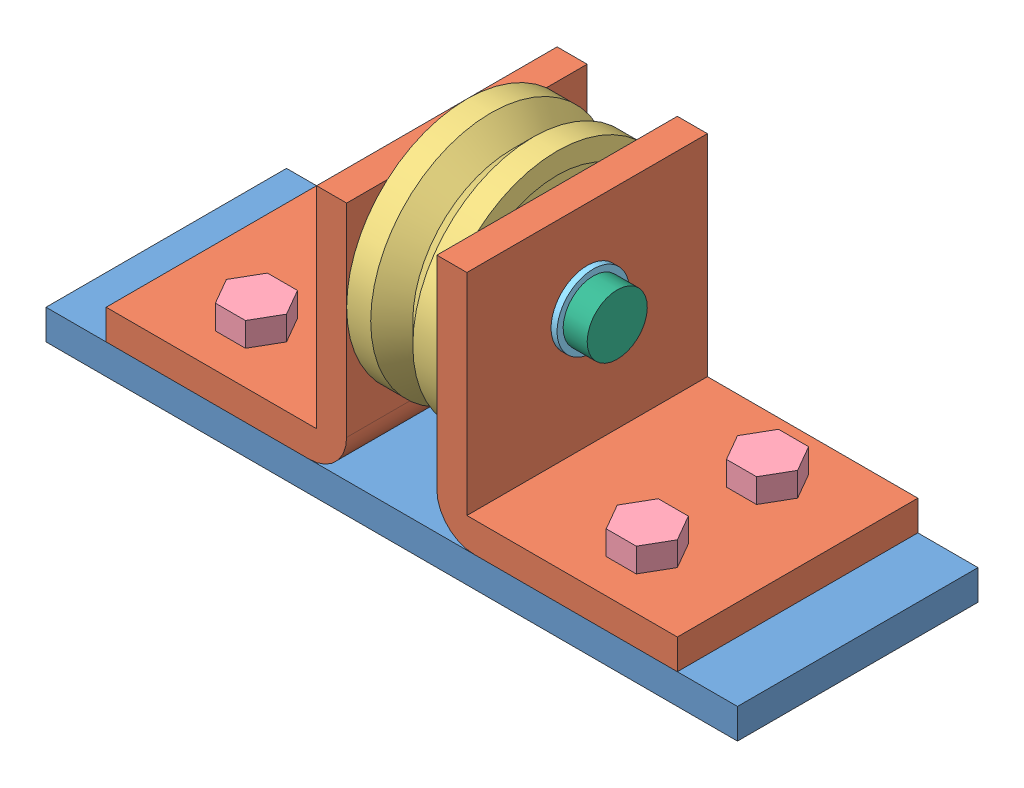
SolidWorks assembly Assem1, configuration Default. Lengths in mm.
Overall size (115 50 40).
13 component instances, 8 part files, 27 mates.
Components (placement in the parent):
- Part1-1: Part1 [Default] at origin size (115 5 40)
- Part2-1: Part2 [Default] at (12.5 7.5 0) size (40 40 40)
- Part2-2: Part2 [Default] at (-12.5 7.5 0) x (-1 0 0) z (0 0 -1) size (40 40 40)
- Part7-1: Part7 [Default] at (0 27.5 0) x (0 0 -1) z (1 0 0) size (40 40 15)
- Part8-1: Part8 [Default] at (32.5 9.5 10) size (10 13 8.66)
- Part8-2: Part8 [Default] at (-32.5 9.5 10) x (-1 0 0) z (0 0 -1) size (10 13 8.66)
- Part8-3: Part8 [Default] at (32.5 9.5 -10) size (10 13 8.66)
- Part8-4: Part8 [Default] at (-32.5 9.5 -10) x (-1 0 0) z (0 0 -1) size (10 13 8.66)
- Part6-2: Part6 [Default] at (13.5 27.5 0) x (0 1 0) z (0 0 1) size (12 1 12)
- Part3-2: Part3 [Default] at (17.5 27.5 0) x (1 0 0) z (0 -0.360512 0.932754) size (37 10 10)
- Part6-3: Part6 [Default] at (-13.5 27.5 0) x (0 -1 0) z (0 0 1) size (12 1 12)
- Part4-3: Part4 [Default] at (-16 27.5 0) x (0 1 0) z (0 0 1) size (11 5 8.66)
- Part5-4: Part5 [Default] at (-10 27.5 0) x (0 1 0) z (0 0 1) size (10 5 10)
Mates (geometry in assembly coordinates):
- Coincident1: coincident anti-aligned: plane of Part1-1 through (0 2.5 0) normal (0 1 0); plane of Part2-1 through (47.5 2.5 20) normal (0 -1 0)
- Concentric1: concentric aligned: cylinder of Part1-1 through (32.5 -2.501 10) axis (0 1 0) radius 2.5; cylinder of Part2-1 through (32.5 2.499 10) axis (0 1 0) radius 2.5
- Coincident2: coincident anti-aligned: plane of Part1-1 through (0 2.5 0) normal (0 1 0); plane of Part2-2 through (-47.5 2.5 -20) normal (0 -1 0)
- Concentric2: concentric aligned: cylinder of Part1-1 through (-32.5 -2.501 -10) axis (0 1 0) radius 2.5; cylinder of Part2-2 through (-32.5 2.499 -10) axis (0 1 0) radius 2.5
- Concentric3: concentric aligned: cylinder of Part1-1 through (-32.5 -2.501 10) axis (0 1 0) radius 2.5; cylinder of Part2-2 through (-32.5 2.499 10) axis (0 1 0) radius 2.5
- Concentric4: concentric aligned: cylinder of Part1-1 through (32.5 -2.501 -10) axis (0 1 0) radius 2.5; cylinder of Part2-1 through (32.5 2.499 -10) axis (0 1 0) radius 2.5
- Coincident4: coincident anti-aligned: plane of Part2-2 through (-7.5 8.75 -20) normal (1 0 0); plane of Part7-1 through (-7.5 7.5 0) normal (-1 0 0)
- Coincident5: coincident anti-aligned: plane of Part7-1 through (0 27.5 0) normal (0 0 -1); plane of assembly through (0 0 0) normal (0 0 1)
- Concentric7: concentric aligned: cylinder of Part2-1 through (32.5 2.499 10) axis (0 1 0) radius 2.5; cylinder of Part8-1 through (32.5 -1.5 10) axis (0 1 0) radius 2.5
- Coincident6: coincident anti-aligned: plane of Part2-1 through (12.5 7.5 20) normal (0 1 0); plane of Part8-1 through (32.5 7.5 10) normal (0 -1 0)
- Coincident12: coincident anti-aligned: plane of Part2-1 through (12.5 42.5 20) normal (1 0 0); plane of Part6-2 through (12.5 27.5 0) normal (-1 0 0)
- Concentric11: concentric anti-aligned: cylinder of Part2-1 through (7.499 27.5 0) axis (1 0 0) radius 5; circle of Part6-2
- Concentric12: concentric anti-aligned: circle of Part2-1; cylinder of Part3-2 through (-26.5471 27.5 0) axis (-1 0 0) radius 3.125
- Coincident13: coincident anti-aligned: plane of Part6-2 through (13.5 27.5 0) normal (1 0 0); plane of Part3-2 through (13.5 25.6974 4.6638) normal (-1 0 0)
- Coincident18: coincident anti-aligned: plane of Part2-2 through (-12.5 42.5 -20) normal (-1 0 0); plane of Part6-3 through (-12.5 27.5 0) normal (1 0 0)
- Concentric14: concentric anti-aligned: cylinder of Part3-2 through (-26.5471 27.5 0) axis (-1 0 0) radius 2; circle of Part6-3
- Concentric17: concentric anti-aligned: cylinder of Part3-2 through (-26.5471 27.5 0) axis (-1 0 0) radius 2; cylinder of Part4-3 through (-18.5 27.5 0) axis (1 0 0) radius 2
- Coincident21: coincident anti-aligned: plane of Part6-3 through (-13.5 27.5 0) normal (-1 0 0); plane of Part4-3 through (-13.5 27.5 0) normal (1 0 0)
- Lock1: lock: unknown of Part8-1
- Lock2: lock: unknown of Part6-2
- Concentric18: concentric anti-aligned: cylinder of Part2-2 through (-7.499 27.5 0) axis (-1 0 0) radius 5; cylinder of Part7-1 through (54.955 27.5 0) axis (1 0 0) radius 3.125
- Concentric19: concentric anti-aligned: cylinder of Part3-2 through (-26.5471 27.5 0) axis (-1 0 0) radius 5; cylinder of Part5-4 through (-12.5 27.5 0) axis (1 0 0) radius 5
- Coincident22: coincident anti-aligned: plane of Part7-1 through (-7.5 22.5 0) normal (-1 0 0); plane of Part5-4 through (-7.5 27.5 0) normal (1 0 0)
- Lock3: lock: unknown of Part3-2
- Lock4: lock: unknown of Part6-3
- Lock5: lock: unknown of Part4-3
- Lock6: lock: unknown of Part5-4
